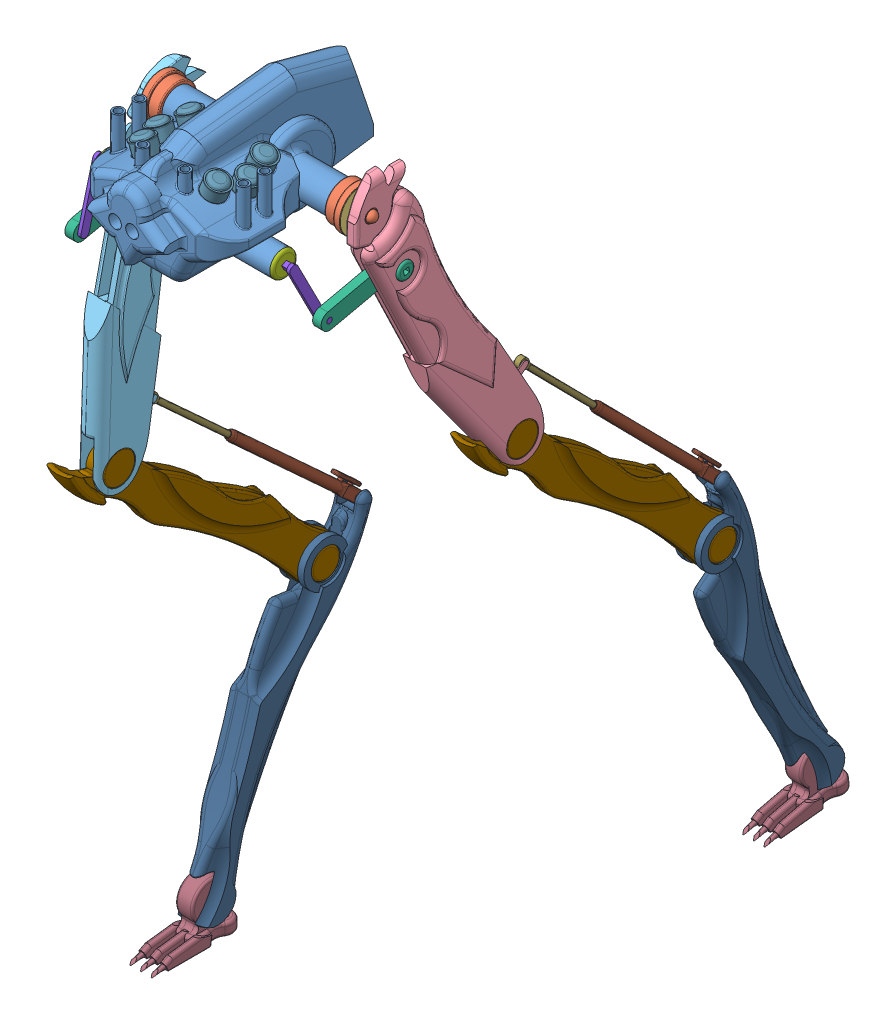
SolidWorks assembly canine rear end assembly, configuration Default. Lengths in mm.
Overall size (300.66 981.12 737.21).
29 component instances, 14 part files, 50 mates.
Components (placement in the parent):
- hind quarters-1: hind quarters [Default] at origin size (223.52 141.12 290.2)
- rear brushless hub motor-1: rear brushless hub motor [Default] at (99.06 -5.0738 -138.7243) x (1 0 0) z (0 -0.469696 0.882828) size (39.37 50.8 50.8)
- rear brushless hub motor cap-1: rear brushless hub motor cap [Default] at (119.38 -5.0738 -138.7243) x (1 0 0) z (0 0.469696 -0.882828) size (2.92 50.8 50.8)
- rear brushless hub motor cap-2: rear brushless hub motor cap [Default] at (-119.38 -5.0738 -138.7243) x (-1 0 0) z (0 0.843068 -0.537807) size (2.92 50.8 50.8)
- rear brushless hub motor-2: rear brushless hub motor [Default] at (-99.06 -5.0738 -138.7243) x (-1 0 0) z (0 -0.843068 0.537807) size (39.37 50.8 50.8)
- upper rear left leg-1: upper rear left leg [Default] at (120.015 -5.0738 -138.7243) x (1 0 0) z (0 -0.590367 0.807135) size (35.47 408.3 128.58)
- upper rear right leg-1: upper rear right leg [Default] at (-94.615 -5.0738 -138.7243) x (1 0 0) z (0 0.033591 0.999436) size (35.47 408.3 128.58)
- upper rear leg slider control bar-1: upper rear leg slider control bar [Default] at (122.936 -74.9082 -172.3208) x (1 0 0) z (0 -0.216846 0.976206) size (27.94 20.32 101.6)
- rear leg motion controller-1: rear leg motion controller [Default] at (78.74 -29.21 -60.599) x (1 0 0) z (0 -0.455228 0.890375) size (28.55 30.48 30.48)
- rear leg motion control rod-1: rear leg motion control rod [Default] at (114.808 -29.21 -60.599) x (1 0 0) z (0 0.890375 0.455228) size (26.67 10.16 81.28)
- rear leg motion controller-2: rear leg motion controller [Default] at (-78.74 -29.21 -60.599) x (-1 0 0) z (0 0.967582 -0.252559) size (28.55 30.48 30.48)
- rear leg motion control rod-2: rear leg motion control rod [Default] at (-114.808 -29.21 -60.599) x (-1 0 0) z (0 0.967582 -0.252559) size (26.67 10.16 81.28)
- upper rear leg slider control bar-2: upper rear leg slider control bar [Default] at (-122.936 -80.7568 -122.0616) x (-1 0 0) z (0 -0.212446 0.977173) size (27.94 20.32 101.6)
- middle rear leg-1: middle rear leg [Default] at (125.476 -319.3155 -312.5054) x (1 0 0) z (0 -0.721556 0.692356) size (41.3 413.23 74.4)
- middle rear leg-2: middle rear leg [Default] at (-125.476 -359.5827 -81.5306) x (1 0 0) z (0 -0.743428 0.668816) size (41.3 413.23 74.4)
- lower rear leg-1: lower rear leg [Default] at (125.476 -547.9316 -550.7631) x (1 0 0) z (0 -0.364792 0.931089) size (49.71 405.22 76.89)
- lower rear leg-2: lower rear leg [Default] at (-125.476 -580.4259 -327.0104) x (1 0 0) z (0 0.439393 0.898295) size (49.71 405.22 76.89)
- lower rear leg motion sensor controller-1: lower rear leg motion sensor controller [Default] at (125.476 -485.3824 -554.1698) x (1 0 0) z (0 -0.702141 0.712038) size (20.32 209.55 18.41)
- lower rear leg motion sensor controller-2: lower rear leg motion sensor controller [Default] at (-125.476 -540.6462 -375.4002) x (1 0 0) z (0 -0.73705 0.675838) size (20.32 209.55 18.41)
- lower rear leg control rod-1: lower rear leg control rod [Default] at (125.476 -252.9969 -325.0145) x (1 0 0) z (0 0.712038 0.702141) size (6.74 11.43 217.51)
- lower rear leg control rod-2: lower rear leg control rod [Default] at (-125.476 -317.6586 -132.2163) x (1 0 0) z (0 0.675838 0.73705) size (6.74 11.43 217.51)
- rear claws-1: rear claws [Default] at (125.476 -838.2174 -672.0258) x (1 0 0) z (0 -0.108311 0.994117) size (34.48 64.13 105.72)
- rear claws-2: rear claws [Default] at (-125.476 -866.0366 -195.1127) size (34.48 64.13 105.72)
- fluids container-1: fluids container [Default] at (25.9582 -13.2367 -42.5839) x (0.929939 -0.367713 -0.000069) z (-0.000069 -0.000362 1) size (26.67 57.15 26.67)
- fluids container-2: fluids container [Default] at (35.4101 -16.9633 -70.5239) x (0.929939 -0.367713 -0.000069) z (-0.000069 -0.000362 1) size (26.67 57.15 26.67)
- fluids container-3: fluids container [Default] at (25.9656 -13.2179 -98.4639) x (0.929939 -0.367713 -0.000069) z (-0.000069 -0.000362 1) size (26.67 57.15 26.67)
- fluids container-4: fluids container [Default] at (-25.9656 -13.2179 -98.4639) x (0.929939 0.367713 0.000069) z (0.000069 -0.000362 1) size (26.67 57.15 26.67)
- fluids container-5: fluids container [Default] at (-35.4101 -16.9633 -70.5239) x (0.929939 0.367713 0.000069) z (0.000069 -0.000362 1) size (26.67 57.15 26.67)
- fluids container-6: fluids container [Default] at (-25.9582 -13.2367 -42.5839) x (0.929939 0.367713 0.000069) z (0.000069 -0.000362 1) size (26.67 57.15 26.67)
Mates (geometry in assembly coordinates):
- Coincident1: coordinate: point of hind quarters-1; point of assembly
- Coincident2: coincident aligned: circle of hind quarters-1; circle of rear brushless hub motor-1
- Coincident3: coincident anti-aligned: circle of rear brushless hub motor-1; circle of rear brushless hub motor cap-1
- Coincident4: coincident anti-aligned: cylinder of rear brushless hub motor-1 through (132.08 -5.0738 -138.7243) axis (-1 0 0) radius 7.62; circle of rear brushless hub motor cap-1
- Coincident5: coincident anti-aligned: circle of hind quarters-1; circle of rear brushless hub motor-2
- Coincident6: coincident anti-aligned: circle of rear brushless hub motor cap-2; circle of rear brushless hub motor-2
- Concentric1: concentric anti-aligned: circle of rear brushless hub motor cap-2; cylinder of rear brushless hub motor-2 through (-132.08 -5.0738 -138.7243) axis (1 0 0) radius 7.62
- Concentric3: concentric aligned: cylinder of rear brushless hub motor-1 through (132.08 -5.0738 -138.7243) axis (-1 0 0) radius 7.62; cylinder of upper rear left leg-1 through (132.207 -5.0738 -138.7243) axis (-1 0 0) radius 7.62
- Coincident8: coincident anti-aligned: plane of rear brushless hub motor cap-1 through (120.015 -5.0738 -138.7243) normal (1 0 0); plane of upper rear left leg-1 through (120.015 -5.0738 -138.7243) normal (-1 0 0)
- Concentric4: concentric aligned: cylinder of rear brushless hub motor-2 through (-132.08 -5.0738 -138.7243) axis (1 0 0) radius 7.62; cylinder of upper rear right leg-1 through (-132.207 -5.0738 -138.7243) axis (1 0 0) radius 7.62
- Coincident9: coincident anti-aligned: plane of rear brushless hub motor cap-2 through (-120.015 -5.0738 -138.7243) normal (-1 0 0); plane of upper rear right leg-1 through (-120.015 -5.0738 -138.7243) normal (1 0 0)
- Coincident10: coincident aligned: plane of upper rear left leg-1 through (112.776 -41.4915 -158.6497) normal (-1 0 0); plane of upper rear leg slider control bar-1 through (112.776 -74.9082 -172.3208) normal (-1 0 0)
- Coincident11: coincident aligned: circle of hind quarters-1; circle of rear leg motion controller-1
- Concentric5: concentric anti-aligned: cylinder of upper rear leg slider control bar-1 through (112.776 -92.5335 -92.9748) axis (1 0 0) radius 3.175; cylinder of rear leg motion control rod-1 through (128.016 -92.5335 -92.9748) axis (-1 0 0) radius 3.175
- Concentric7: concentric aligned: cylinder of upper rear left leg-1 through (139.446 -74.9082 -172.3208) axis (-1 0 0) radius 10.16; cylinder of upper rear leg slider control bar-1 through (133.096 -74.9082 -172.3208) axis (-1 0 0) radius 10.16
- Coincident13: coincident anti-aligned: plane of rear leg motion controller-1 through (94.5896 -33.4823 -59.2174) normal (0 0.455228 -0.890375); plane of rear leg motion control rod-1 through (101.346 -27.8284 -56.3267) normal (0 -0.455228 0.890375)
- Coincident14: coincident anti-aligned: plane of rear leg motion controller-1 through (94.5896 -33.4823 -59.2174) normal (0 0.890375 0.455228); plane of rear leg motion control rod-1 through (101.346 -30.5916 -64.8713) normal (0 -0.890375 -0.455228)
- LimitAngle1: limit planar angle = 1.098169 rad aligned: plane of assembly through (0 0 0) normal (0 1 0); plane of rear leg motion control rod-1 through (114.046 -26.8974 -65.1221) normal (0 0.455228 -0.890375)
- Coincident15: coincident anti-aligned: circle of hind quarters-1; circle of rear leg motion controller-2
- Parallel1: parallel anti-aligned: plane of rear leg motion controller-2 through (-107.2896 -29.21 -60.599) normal (-1 0 0); plane of rear leg motion control rod-2 through (-114.046 -29.21 -60.599) normal (1 0 0)
- Coincident17: coincident anti-aligned: plane of rear leg motion controller-2 through (-94.5896 -25.3361 -58.3288) normal (0 -0.252559 -0.967582); plane of rear leg motion control rod-2 through (-101.346 -25.3361 -58.3288) normal (0 0.252559 0.967582)
- Coincident18: coincident anti-aligned: plane of rear leg motion controller-2 through (-94.5896 -33.0839 -62.8692) normal (0 0.967582 -0.252559); plane of rear leg motion control rod-2 through (-101.346 -31.4802 -56.725) normal (0 -0.967582 0.252559)
- Coincident19: coincident aligned: circle of rear leg motion control rod-2; circle of upper rear leg slider control bar-2
- Coincident20: coincident anti-aligned: plane of upper rear right leg-1 through (-117.856 -84.3092 -247.4175) normal (-1 0 0); plane of upper rear leg slider control bar-2 through (-117.856 -98.0244 -42.637) normal (1 0 0)
- Concentric8: concentric aligned: cylinder of upper rear right leg-1 through (-139.446 -80.7568 -122.0616) axis (1 0 0) radius 10.16; cylinder of upper rear leg slider control bar-2 through (-133.096 -80.7568 -122.0616) axis (1 0 0) radius 10.16
- LimitAngle2: limit planar angle = 1.82612 rad aligned: plane of rear leg motion control rod-2 through (-114.046 -30.493 -65.5143) normal (0 -0.252559 -0.967582); plane of assembly through (0 0 0) normal (0 1 0)
- Concentric9: concentric anti-aligned: cylinder of upper rear left leg-1 through (75.184 -319.3155 -312.5054) axis (1 0 0) radius 19.05; cylinder of middle rear leg-1 through (139.446 -319.3155 -312.5054) axis (-1 0 0) radius 19.05
- Coincident21: coincident aligned: plane of upper rear left leg-1 through (139.446 -319.4942 -264.0132) normal (1 0 0); plane of middle rear leg-1 through (139.446 -319.3155 -312.5054) normal (1 0 0)
- Coincident22: coincident aligned: plane of upper rear right leg-1 through (-111.506 -329.7966 -43.2644) normal (1 0 0); plane of middle rear leg-2 through (-111.506 -359.5827 -81.5306) normal (1 0 0)
- Concentric10: concentric anti-aligned: cylinder of upper rear right leg-1 through (-139.446 -359.5827 -81.5306) axis (1 0 0) radius 19.05; cylinder of middle rear leg-2 through (-111.506 -359.5827 -81.5306) axis (-1 0 0) radius 19.05
- Concentric11: concentric anti-aligned: cylinder of middle rear leg-1 through (110.236 -547.9316 -550.7631) axis (1 0 0) radius 17.78; cylinder of lower rear leg-1 through (140.716 -547.9316 -550.7631) axis (-1 0 0) radius 17.78
- Coincident23: coincident aligned: plane of middle rear leg-1 through (140.716 -547.9316 -550.7631) normal (1 0 0); plane of lower rear leg-1 through (140.716 -547.9316 -550.7631) normal (1 0 0)
- Concentric12: concentric anti-aligned: cylinder of middle rear leg-2 through (-140.716 -580.4259 -327.0104) axis (1 0 0) radius 17.78; cylinder of lower rear leg-2 through (-110.236 -580.4259 -327.0104) axis (-1 0 0) radius 17.78
- Coincident24: coincident aligned: plane of middle rear leg-2 through (-110.236 -580.4259 -327.0104) normal (1 0 0); plane of lower rear leg-2 through (-110.236 -580.4259 -327.0104) normal (1 0 0)
- LimitAngle3: limit planar angle = 0.432637 rad aligned: plane of middle rear leg-1 through (125.476 -319.3155 -312.5054) normal (0 -0.721556 0.692356); plane of lower rear leg-1 through (125.476 -547.9316 -550.7631) normal (0 -0.364792 0.931089)
- LimitAngle4: limit planar angle = 1.293104 rad aligned: plane of middle rear leg-2 through (-125.476 -359.5827 -81.5306) normal (0 -0.743428 0.668816); plane of lower rear leg-2 through (-125.476 -580.4259 -327.0104) normal (0 0.439393 0.898295)
- LimitAngle5: limit planar angle = 0.174533 rad aligned: plane of upper rear left leg-1 through (120.015 -5.0738 -138.7243) normal (0 -0.590367 0.807135); plane of middle rear leg-1 through (125.476 -319.3155 -312.5054) normal (0 -0.721556 0.692356)
- LimitAngle6: limit planar angle = 0.871778 rad aligned: plane of upper rear right leg-1 through (-94.615 -5.0738 -138.7243) normal (0 0.033591 0.999436); plane of middle rear leg-2 through (-125.476 -359.5827 -81.5306) normal (0 -0.743428 0.668816)
- Coincident25: coincident aligned: circle of lower rear leg-1; circle of lower rear leg motion sensor controller-1
- Coincident26: coincident aligned: circle of lower rear leg-2; circle of lower rear leg motion sensor controller-2
- Concentric13: concentric anti-aligned: cylinder of lower rear leg motion sensor controller-1 through (125.476 -339.792 -410.6031) axis (0 -0.712038 -0.702141) radius 5.715; cylinder of lower rear leg control rod-1 through (125.476 -403.8042 -473.7256) axis (0 0.712038 0.702141) radius 3.175
- Coincident27: coincident aligned: circle of upper rear right leg-1; circle of lower rear leg control rod-2
- Concentric15: concentric anti-aligned: cylinder of lower rear leg motion sensor controller-2 through (-125.476 -402.4575 -224.6956) axis (0 -0.675838 -0.73705) radius 5.715; cylinder of lower rear leg control rod-2 through (-125.476 -460.7989 -288.321) axis (0 0.675838 0.73705) radius 3.175
- Coincident28: coincident anti-aligned: circle of upper rear left leg-1; circle of lower rear leg control rod-1
- Coincident29: coincident aligned: circle of lower rear leg-1; circle of rear claws-1
- Coincident30: coincident aligned: plane of upper rear leg slider control bar-1 through (128.016 -92.5335 -92.9748) normal (1 0 0); plane of rear leg motion control rod-1 through (128.016 -92.5335 -92.9748) normal (1 0 0)
- Coincident31: coincident anti-aligned: circle of lower rear leg-2; circle of rear claws-2
- Coincident32: coincident anti-aligned: circle of hind quarters-1; circle of fluids container-1
- Coincident33: coincident anti-aligned: circle of hind quarters-1; circle of fluids container-2
- Coincident34: coincident anti-aligned: circle of hind quarters-1; circle of fluids container-3
